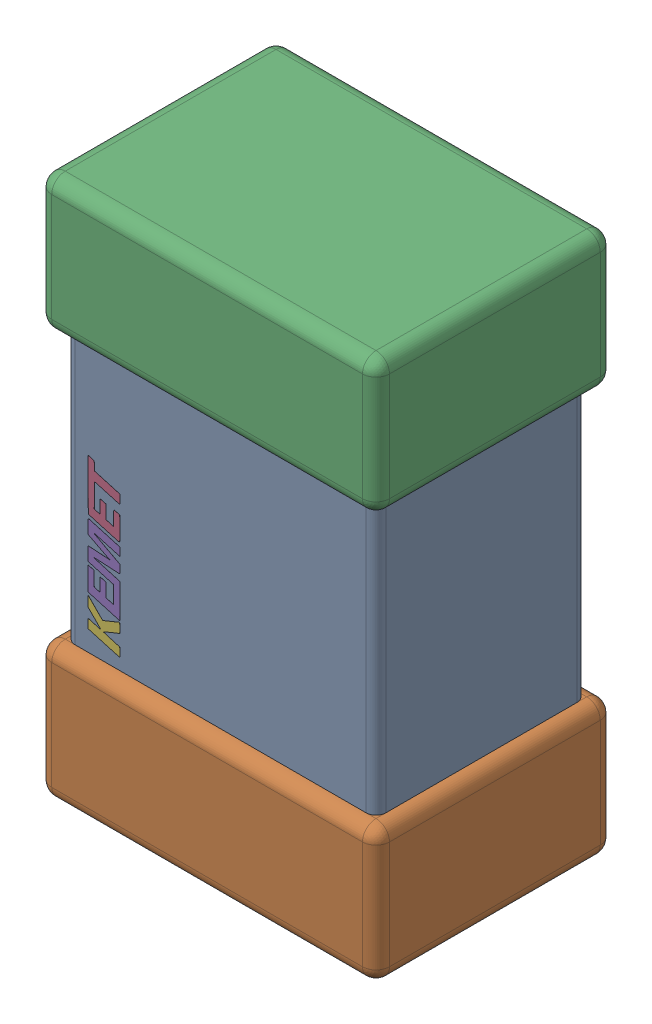
SolidWorks assembly C2.step, configuration Default. Lengths in mm.
Overall size (1.25 2 0.88).
3 component instances, 3 part files, 0 mates.
Components (placement in the parent):
- Cap_KEMET_C0805C472J3HAC_eec.step-1: Cap_KEMET_C0805C472J3HAC_eec.step [Default] at (11.894 65.924 0) x (0 1 0) z (0 0 1) size (1 1.15 0.78)
- Cap_KEMET_C0805C472J3HAC_eec-7.step-1: Cap_KEMET_C0805C472J3HAC_eec-7.step [Default] at (11.894 65.924 0) x (0 1 0) z (0 0 1) size (2 1.25 0.88)
- Cap_KEMET_C0805C472J3HAC_eec-8.step-1: Cap_KEMET_C0805C472J3HAC_eec-8.step [Default] at (11.894 65.924 0) x (0 1 0) z (0 0 1) size (0.59 0.12 0)
